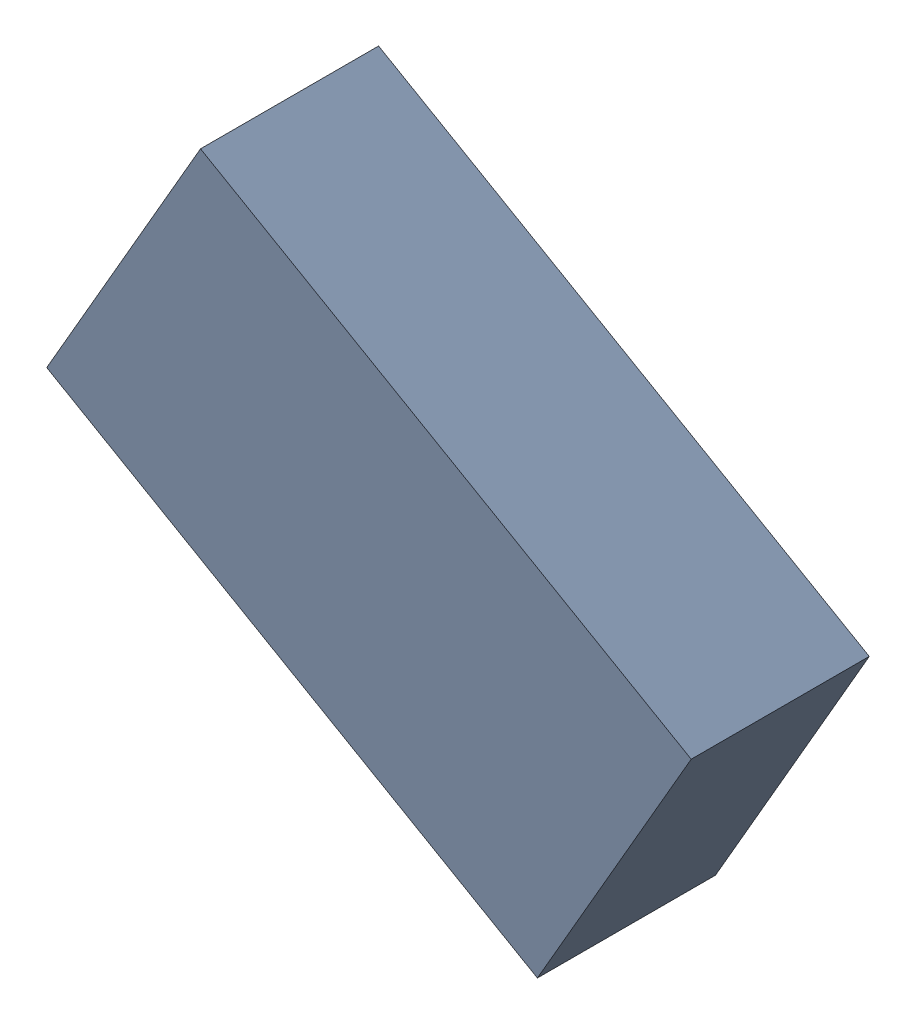
SolidWorks assembly L3_TDA3, configuration Standard. Lengths in mm.
Overall size (1.99 1.7 0.55).
2 component instances, 1 part files, 0 mates.
Components (placement in the parent):
- 885543872-1: 885543872 [Standard] at (47.6699 -34.1046 0) size (1.99 1.7 0.55)
  - Extruded_20-1: Extruded_20 [Standard] at origin size (1.99 1.7 0.55)
